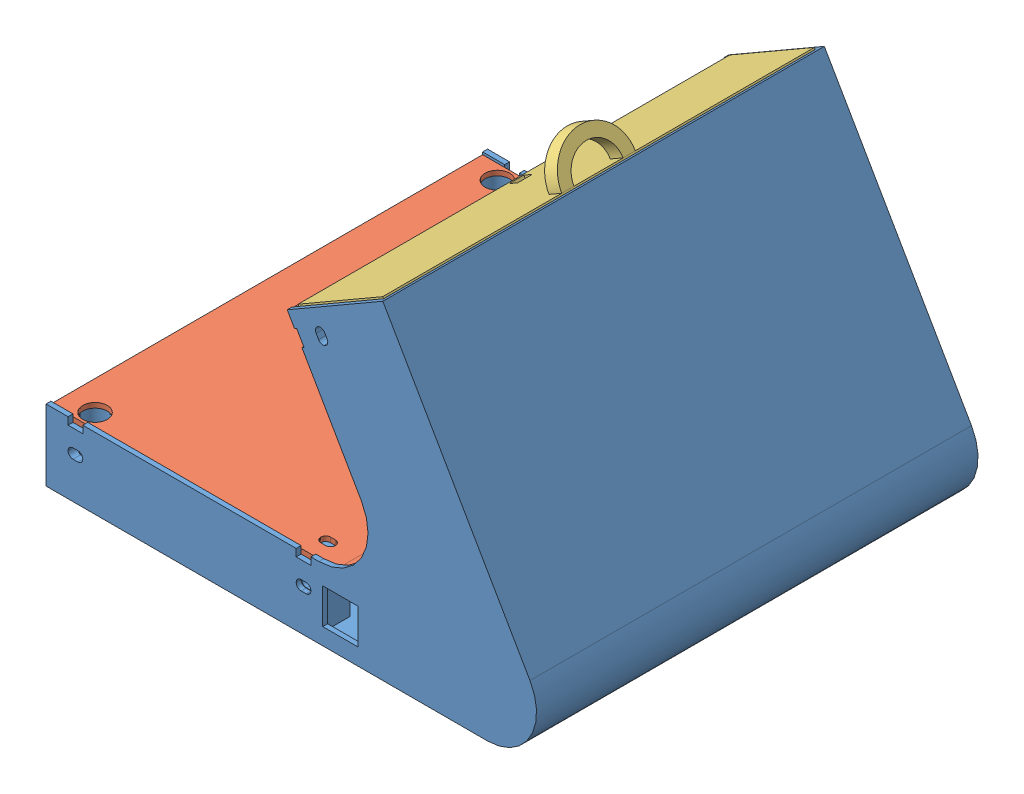
SolidWorks assembly Meteo, configuration Domyślna. Lengths in mm.
Overall size (134.06 73.25 90).
3 component instances, 3 part files, 6 mates.
Components (placement in the parent):
- meteoStation-1: meteoStation [Domyślna] at (-2.6804 -18.3042 100) size (100 66.96 90)
- meteoStation_back-1: meteoStation_back [Domyślna] at (-27.5452 -5.3042 101) size (134.06 43.47 88)
- Meteo_drawer-1: Meteo_drawer [Domyślna] at (11.706 47.1493 182.5) x (0 0 1) z (0.5 -0.866025 0) size (88 19.9 66)
Mates (geometry in assembly coordinates):
- Wspólnie1: coincident anti-aligned: plane of meteoStation-1 through (-52.1702 -5.3042 100) normal (0 1 0); plane of meteoStation_back-1 through (-56.6702 -5.3042 189) normal (0 -1 0)
- Koncentryczne1: concentric aligned: cylinder of meteoStation-1 through (-50.6702 -15.3042 186) axis (0 1 0) radius 2.5; cylinder of meteoStation_back-1 through (-50.6702 -5.3042 186) axis (0 1 0) radius 2.5
- Koncentryczne2: concentric aligned: cylinder of meteoStation-1 through (-50.6702 -15.3042 104) axis (0 1 0) radius 2.5; cylinder of meteoStation_back-1 through (-50.6702 -5.3042 104) axis (0 1 0) radius 2.5
- Szerokość1: width anti-aligned: plane of Meteo_drawer-1 through (40.206 -2.2141 107.5) normal (0 0 -1); plane of meteoStation-1 through (40.206 -2.2141 182.5) normal (0 0 1); plane of Meteo_drawer-1 through (-5.4465 36.8582 107) normal (0 0 1); plane of meteoStation-1 through (-5.4465 36.8582 183) normal (0 0 -1)
- Wspólnie2: coincident anti-aligned: plane of meteoStation-1 through (41.124 -3.8042 190) normal (-0.866025 -0.5 0); plane of Meteo_drawer-1 through (40.206 -2.2141 182.5) normal (0.866025 0.5 0)
- Wspólnie3: coincident anti-aligned: plane of meteoStation-1 through (-5.4465 36.8582 101) normal (-0.5 0.866025 0); plane of Meteo_drawer-1 through (11.874 46.8582 182.5) normal (0.5 -0.866025 0)
